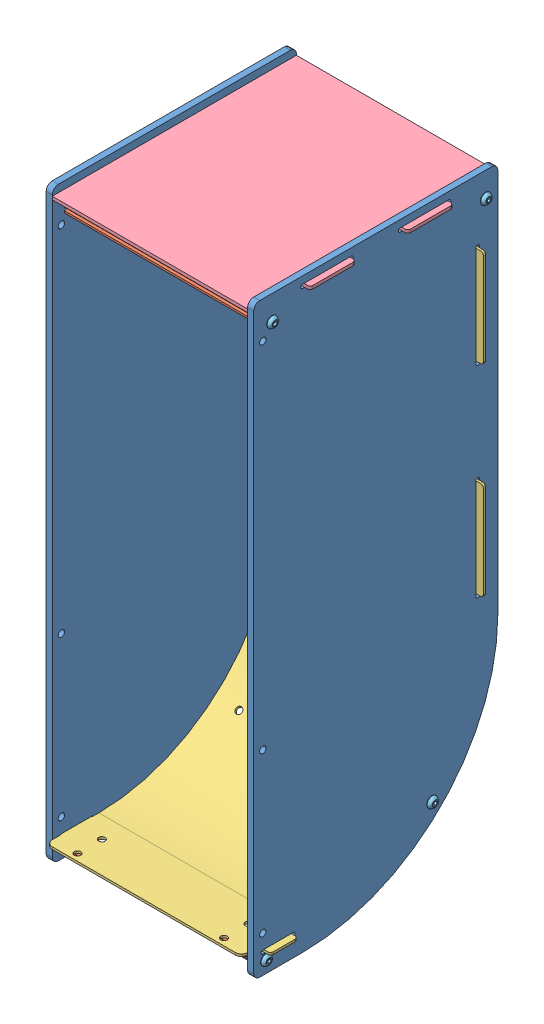
SolidWorks assembly GE-20205, configuration Default. Lengths in mm.
Overall size (228.6 609.6 260.35).
16 component instances, 5 part files, 36 mates.
Components (placement in the parent):
- GE-20206-1: GE-20206 [Default] at (212.6585 1853.7935 1228.0332) size (6.35 609.6 254)
- GE-20209-1: GE-20209 [Default] at (-92.1415 1828.3935 986.7332) x (0 -0.5 -0.866025) z (1 0 0) size (14.66 12.7 203.2)
- GE-20209-3: GE-20209 [Default] at (-92.1415 1312.6897 1042.5293) x (0 -0.258819 -0.965926) z (1 0 0) size (14.66 12.7 203.2)
- GE-20209-4: GE-20209 [Default] at (-92.1415 1256.8935 1215.3332) x (0 -0.866025 0.5) z (1 0 0) size (14.66 12.7 203.2)
- GE-20209-6: GE-20209 [Default] at (-92.1415 1828.3935 1208.9832) x (0 -0.5 -0.866025) z (1 0 0) size (14.66 12.7 203.2)
- GE-20207-1: GE-20207 [Default] at (111.0585 1644.2435 995.4454) size (228.6 573.86 241.3)
- GE-20208-1: GE-20208 [Default] at (9.4585 1842.9985 974.0332) size (228.6 3.17 254)
- GE-20206-2: GE-20206 [Default] at (3.1085 1853.7935 1228.0332) size (6.35 609.6 254)
- round_hex_.25_20_.625_full-1: round_hex_.25_20_.625_full [91255A539] at (222.3613 1828.3935 1208.9832) x (0 0 -1) z (1 0 0) size (11.1 11.1 19.46)
- round_hex_.25_20_.625_full-2: round_hex_.25_20_.625_full [91255A539] at (222.3613 1828.3935 986.7332) x (0 0.158553 -0.987351) z (1 0 0) size (11.1 11.1 19.46)
- round_hex_.25_20_.625_full-4: round_hex_.25_20_.625_full [91255A539] at (222.3613 1256.8935 1215.3332) x (0 0.282984 -0.959125) z (1 0 0) size (11.1 11.1 19.46)
- round_hex_.25_20_.625_full-6: round_hex_.25_20_.625_full [91255A539] at (222.3613 1312.6897 1042.5293) x (0 0.371154 -0.928571) z (1 0 0) size (11.1 11.1 19.46)
- round_hex_.25_20_.625_full-9: round_hex_.25_20_.625_full [91255A539] at (-0.2443 1256.8935 1215.3332) x (0 0.421154 0.906989) z (-1 0 0) size (11.1 11.1 19.46)
- round_hex_.25_20_.625_full-11: round_hex_.25_20_.625_full [91255A539] at (-0.2443 1312.6897 1042.5293) x (0 0.429957 0.902849) z (-1 0 0) size (11.1 11.1 19.46)
- round_hex_.25_20_.625_full-13: round_hex_.25_20_.625_full [91255A539] at (-0.2443 1828.3935 986.7332) x (0 0.39282 0.919615) z (-1 0 0) size (11.1 11.1 19.46)
- round_hex_.25_20_.625_full-15: round_hex_.25_20_.625_full [91255A539] at (-0.2443 1828.3935 1208.9832) x (0 0.305088 0.952324) z (-1 0 0) size (11.1 11.1 19.46)
Mates (geometry in assembly coordinates):
- Coincident2: coincident anti-aligned: plane of SidePlate1-1 through (212.6585 1447.3935 1177.2332) normal (-1 0 0); plane of Churro-1 through (212.6585 1828.3935 980.3832) normal (1 0 0)
- Concentric3: concentric anti-aligned: cylinder of SidePlate1-1 through (212.6585 1828.3935 986.7332) axis (1 0 0) radius 3.3655; cylinder of Churro-1 through (212.6585 1828.3935 986.7332) axis (-1 0 0) radius 2.9337
- Coincident7: coincident anti-aligned: plane of SidePlate1-1 through (212.6585 1447.3935 1177.2332) normal (-1 0 0); plane of Churro-3 through (212.6585 1314.3332 1036.3957) normal (1 0 0)
- Concentric5: concentric anti-aligned: circle of SidePlate1_angled-1; cylinder of Churro-3 through (212.6585 1312.6897 1042.5293) axis (-1 0 0) radius 2.9337
- Coincident9: coincident anti-aligned: plane of SidePlate1-1 through (212.6585 1447.3935 1177.2332) normal (-1 0 0); plane of Churro-4 through (212.6585 1250.5435 1215.3332) normal (1 0 0)
- Concentric6: concentric anti-aligned: cylinder of SidePlate1-1 through (212.6585 1256.8935 1215.3332) axis (1 0 0) radius 3.3655; cylinder of Churro-4 through (212.6585 1256.8935 1215.3332) axis (-1 0 0) radius 2.9337
- Coincident13: coincident anti-aligned: plane of SidePlate1-1 through (212.6585 1447.3935 1177.2332) normal (-1 0 0); plane of Churro-6 through (212.6585 1828.3935 1202.6332) normal (1 0 0)
- Concentric8: concentric anti-aligned: cylinder of SidePlate1-1 through (212.6585 1828.3935 1208.9832) axis (1 0 0) radius 3.3655; cylinder of Churro-6 through (212.6585 1828.3935 1208.9832) axis (-1 0 0) radius 2.9337
- Coincident17: coincident anti-aligned: plane of SidePlate1-1 through (212.6585 1447.3935 1177.2332) normal (-1 0 0); plane of GE-20207-1 through (212.6585 1837.9185 993.0832) normal (1 0 0)
- Coincident18: coincident anti-aligned: plane of Churro-1 through (212.6585 1832.0597 993.0832) normal (0 0 1); plane of GE-20207-1 through (111.0585 1644.2435 993.0832) normal (0 0 -1)
- Distance2: distance = 15.875 mm aligned: plane of SidePlate1-1 through (219.0085 1853.7935 1228.0332) normal (0 1 0); plane of Wall1-1 through (9.4585 1837.9185 993.0832) normal (0 1 0)
- Coincident24: coincident anti-aligned: plane of Top-1 through (212.6585 1846.1735 1228.0332) normal (1 0 0); plane of SidePlate1-1 through (212.6585 1447.3935 1177.2332) normal (-1 0 0)
- Coincident26: coincident aligned: plane of SidePlate1-1 through (219.0085 1447.3935 974.0332) normal (0 0 -1); plane of Top-1 through (212.6585 1846.1735 974.0332) normal (0 0 -1)
- Parallel2: parallel aligned: plane of SidePlate1-1 through (219.0085 1853.7935 1228.0332) normal (0 0 1); plane of Churro-6 through (212.6585 1832.0597 1215.3332) normal (0 0 1)
- Angle1: planar angle = 2.356194 rad anti-aligned: plane of Churro-3 through (212.6585 1309.3221 1036.9167) normal (0 -0.707107 -0.707107); plane of SidePlate1-1 through (219.0085 1447.3935 974.0332) normal (0 0 -1)
- Parallel5: parallel aligned: plane of SidePlate1-1 through (219.0085 1244.1935 1228.0332) normal (0 -1 0); plane of Churro-4 through (212.6585 1250.5435 1213.7457) normal (0 -1 0)
- Coincident33: coincident anti-aligned: plane of Churro-1 through (9.4585 1822.8943 983.5582) normal (-1 0 0); plane of SidePlate1-2 through (9.4585 1447.3935 1177.2332) normal (1 0 0)
- Concentric9: concentric anti-aligned: cylinder of Churro-1 through (212.6585 1828.3935 986.7332) axis (-1 0 0) radius 2.9337; cylinder of SidePlate1-2 through (3.1085 1828.3935 986.7332) axis (1 0 0) radius 3.3655
- Coincident34: coincident anti-aligned: plane of SidePlate1-1 through (212.6585 1846.1735 1177.2332) normal (0 -1 0); plane of Top-1 through (9.4585 1846.1735 974.0332) normal (0 1 0)
- Concentric10: concentric anti-aligned: cylinder of round_hex_.25_20_.625_full-1 through (203.1335 1828.3935 1208.9832) axis (-1 0 0) radius 3.175; cylinder of GE-20206-1 through (212.6585 1828.3935 1208.9832) axis (1 0 0) radius 3.3655
- Coincident35: coincident anti-aligned: plane of GE-20206-1 through (219.0085 1447.3935 1177.2332) normal (1 0 0); plane of round_hex_.25_20_.625_full-1 through (219.0085 1822.8436 1208.9832) normal (-1 0 0)
- Concentric11: concentric anti-aligned: cylinder of GE-20206-1 through (212.6585 1828.3935 986.7332) axis (1 0 0) radius 3.3655; cylinder of round_hex_.25_20_.625_full-2 through (203.1335 1828.3935 986.7332) axis (-1 0 0) radius 3.175
- Coincident36: coincident anti-aligned: plane of GE-20206-1 through (219.0085 1447.3935 1177.2332) normal (1 0 0); plane of round_hex_.25_20_.625_full-2 through (219.0085 1822.9138 985.8532) normal (-1 0 0)
- Concentric12: concentric anti-aligned: cylinder of GE-20206-1 through (212.6585 1256.8935 1215.3332) axis (1 0 0) radius 3.3655; cylinder of round_hex_.25_20_.625_full-4 through (203.1335 1256.8935 1215.3332) axis (-1 0 0) radius 3.175
- Coincident37: coincident anti-aligned: plane of GE-20206-1 through (219.0085 1447.3935 1177.2332) normal (1 0 0); plane of round_hex_.25_20_.625_full-4 through (219.0085 1251.5705 1213.7626) normal (-1 0 0)
- Concentric13: concentric anti-aligned: cylinder of GE-20206-1 through (212.6585 1312.6897 1042.5293) axis (1 0 0) radius 3.3655; cylinder of round_hex_.25_20_.625_full-6 through (203.1335 1312.6897 1042.5293) axis (-1 0 0) radius 3.175
- Coincident38: coincident anti-aligned: plane of GE-20206-1 through (219.0085 1447.3935 1177.2332) normal (1 0 0); plane of round_hex_.25_20_.625_full-6 through (219.0085 1307.5362 1040.4695) normal (-1 0 0)
- Concentric15: concentric aligned: cylinder of GE-20206-2 through (3.1085 1256.8935 1215.3332) axis (1 0 0) radius 3.3655; cylinder of round_hex_.25_20_.625_full-9 through (18.9835 1256.8935 1215.3332) axis (1 0 0) radius 3.175
- Coincident39: coincident anti-aligned: plane of GE-20206-2 through (3.1085 1447.3935 1177.2332) normal (-1 0 0); plane of round_hex_.25_20_.625_full-9 through (3.1085 1251.8598 1217.6705) normal (1 0 0)
- Concentric16: concentric aligned: cylinder of GE-20206-2 through (3.1085 1312.6897 1042.5293) axis (1 0 0) radius 3.3655; cylinder of round_hex_.25_20_.625_full-11 through (18.9835 1312.6897 1042.5293) axis (1 0 0) radius 3.175
- Coincident40: coincident anti-aligned: plane of GE-20206-2 through (3.1085 1447.3935 1177.2332) normal (-1 0 0); plane of round_hex_.25_20_.625_full-11 through (3.1085 1307.679 1044.9155) normal (1 0 0)
- Concentric17: concentric aligned: cylinder of GE-20206-2 through (3.1085 1828.3935 986.7332) axis (1 0 0) radius 3.3655; cylinder of round_hex_.25_20_.625_full-13 through (18.9835 1828.3935 986.7332) axis (1 0 0) radius 3.175
- Coincident41: coincident anti-aligned: plane of GE-20206-2 through (3.1085 1447.3935 1177.2332) normal (-1 0 0); plane of round_hex_.25_20_.625_full-13 through (3.1085 1823.2898 988.9133) normal (1 0 0)
- Concentric18: concentric aligned: cylinder of GE-20206-2 through (3.1085 1828.3935 1208.9832) axis (1 0 0) radius 3.3655; cylinder of round_hex_.25_20_.625_full-15 through (18.9835 1828.3935 1208.9832) axis (1 0 0) radius 3.175
- Coincident42: coincident anti-aligned: plane of GE-20206-2 through (3.1085 1447.3935 1177.2332) normal (-1 0 0); plane of round_hex_.25_20_.625_full-15 through (3.1085 1823.1082 1210.6764) normal (1 0 0)
- Concentric19: concentric aligned: cylinder of GE-20206-1 through (212.6585 1256.8935 1215.3332) axis (1 0 0) radius 3.3655; cylinder of GE-20206-2 through (3.1085 1256.8935 1215.3332) axis (1 0 0) radius 3.3655
